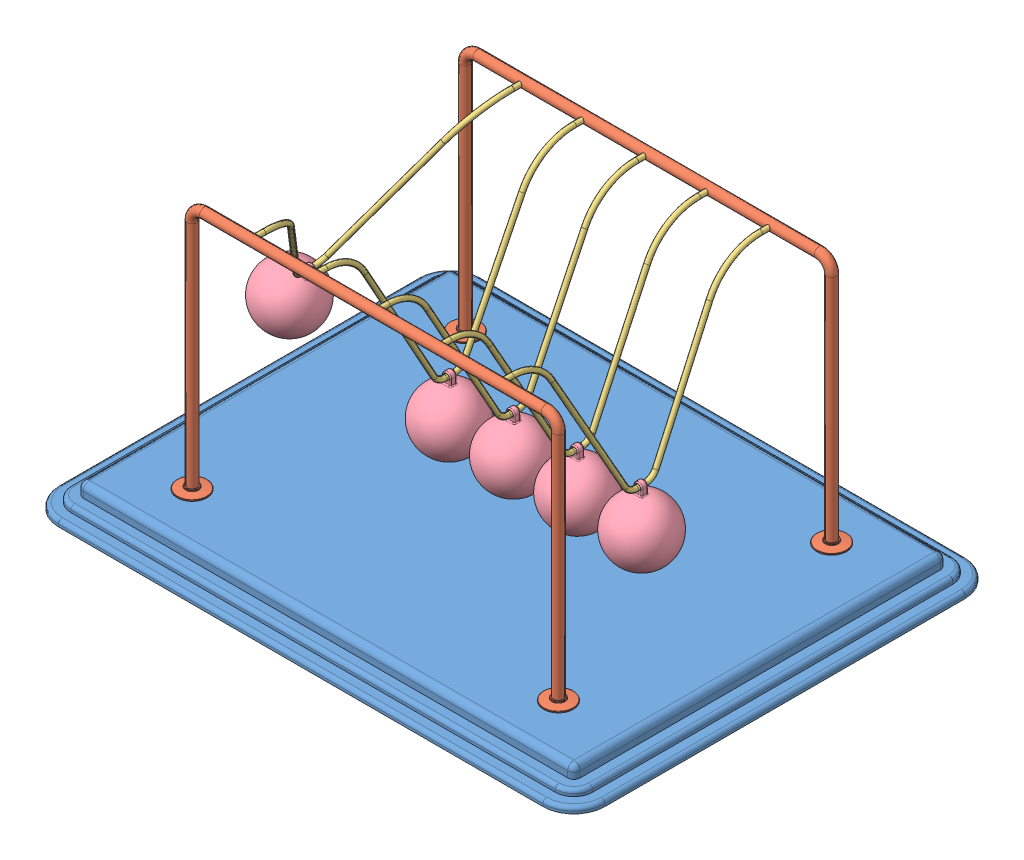
SolidWorks assembly Newtons Cradle NewtonsCradle 0232, configuration Default. Lengths in mm.
Overall size (440 222 340).
13 component instances, 4 part files, 34 mates.
Components (placement in the parent):
- Base NewtonsCradle 0232-1: Base NewtonsCradle 0232 [Default] at (-16.2968 -4.1587 11.425) size (440 20 340)
- frame NewtonsCradle 0232-1: frame NewtonsCradle 0232 [Default] at (-16.2968 144.4547 -98.575) size (319 202 24)
- frame NewtonsCradle 0232-2: frame NewtonsCradle 0232 [Default] at (-16.2968 144.4547 121.425) x (-1 0 0) z (0 0 -1) size (319 202 24)
- Hanging thing NewtonsCradle 0232-1: Hanging thing NewtonsCradle 0232 [Default] at (-157.6326 134.1825 11.425) x (0 0 1) z (-0.859985 0.510319 0) size (220 129 4)
- Hanging thing NewtonsCradle 0232-2: Hanging thing NewtonsCradle 0232 [Default] at (-66.576 122.8418 11.425) x (0 0 1) z (-0.999994 0.003446 0) size (220 129 4)
- Hanging thing NewtonsCradle 0232-3: Hanging thing NewtonsCradle 0232 [Default] at (-15.6923 122.8436 11.425) x (0 0 1) z (-0.999972 -0.007464 0) size (220 129 4)
- Hanging thing NewtonsCradle 0232-4: Hanging thing NewtonsCradle 0232 [Default] at (35.2213 122.8555 11.425) x (0 0 1) z (-0.999824 -0.018742 0) size (220 129 4)
- Hanging thing NewtonsCradle 0232-5: Hanging thing NewtonsCradle 0232 [Default] at (86.0287 122.8747 11.425) x (0 0 1) z (-0.999588 -0.028711 0) size (220 129 4)
- Sphere NewtonsCradle 0232-1: Sphere NewtonsCradle 0232 [Default] at (-195.3962 70.5436 11.425) x (0.859985 -0.510319 0) z (0 0 1) size (50 58.5 50)
- Sphere NewtonsCradle 0232-2: Sphere NewtonsCradle 0232 [Default] at (88.1533 48.9052 11.425) x (0.999588 0.028711 0) z (0 0 1) size (50 58.5 50)
- Sphere NewtonsCradle 0232-3: Sphere NewtonsCradle 0232 [Default] at (-15.14 48.8456 11.425) x (0.999972 0.007464 0) z (0 0 1) size (50 58.5 50)
- Sphere NewtonsCradle 0232-4: Sphere NewtonsCradle 0232 [Default] at (36.6081 48.8685 11.425) x (0.999824 0.018742 0) z (0 0 1) size (50 58.5 50)
- Sphere NewtonsCradle 0232-5: Sphere NewtonsCradle 0232 [Default] at (-66.831 48.8422 11.425) x (0.999994 -0.003446 0) z (0 0 1) size (50 58.5 50)
Mates (geometry in assembly coordinates):
- Coincident1: coincident anti-aligned: plane of Base-1 through (-211.2968 5.8413 156.425) normal (0 1 0); plane of frame-2 through (-175.7968 5.8413 121.425) normal (0 -1 0)
- Coincident2: coincident anti-aligned: plane of Base-1 through (-211.2968 5.8413 156.425) normal (0 1 0); plane of frame-1 through (143.2032 5.8413 -98.575) normal (0 -1 0)
- Concentric1: concentric anti-aligned: cylinder of frame-1 through (-116.2968 203.8413 -94.575) axis (0 0 -1) radius 2; cylinder of frame-2 through (-116.2968 203.8413 117.425) axis (0 0 1) radius 2
- Concentric2: concentric anti-aligned: cylinder of frame-1 through (83.7032 203.8413 -94.575) axis (0 0 -1) radius 2; cylinder of frame-2 through (83.7032 203.8413 117.425) axis (0 0 1) radius 2
- Distance1: distance = 60 mm: plane of frame-1 through (-16.2968 144.4547 -98.575) normal (0 0 1); line of Base-1 through (-211.2968 -12.1587 -158.575) axis (1 0 0)
- Distance2: distance = 60 mm: line of Base-1 through (178.7032 -12.1587 181.425) axis (-1 0 0); plane of frame-2 through (-16.2968 144.4547 121.425) normal (0 0 -1)
- Distance3: distance = 220 mm: plane of frame-2 through (-16.2968 144.4547 121.425) normal (-1 0 0); line of Base-1 through (-236.2968 -12.1587 156.425) axis (0 0 -1)
- Concentric3: concentric anti-aligned: cylinder of frame-1 through (-116.2968 203.8413 -94.575) axis (0 0 -1) radius 2; cylinder of Hanging thing-1 through (-116.2968 203.8413 111.425) axis (0 0 1) radius 2
- Concentric4: concentric anti-aligned: cylinder of frame-1 through (-116.2968 203.8413 -94.575) axis (0 0 -1) radius 2; cylinder of Hanging thing-1 through (-116.2968 203.8413 -98.575) axis (0 0 1) radius 2
- Concentric5: concentric aligned: cylinder of frame-2 through (-66.2968 203.8413 117.425) axis (0 0 1) radius 2; cylinder of Hanging thing-2 through (-66.2968 203.8413 111.425) axis (0 0 1) radius 2
- Concentric6: concentric aligned: cylinder of frame-2 through (-16.2968 203.8413 117.425) axis (0 0 1) radius 2; cylinder of Hanging thing-3 through (-16.2968 203.8413 111.425) axis (0 0 1) radius 2
- Concentric7: concentric aligned: cylinder of frame-2 through (33.7032 203.8413 117.425) axis (0 0 1) radius 2; cylinder of Hanging thing-4 through (33.7032 203.8413 111.425) axis (0 0 1) radius 2
- Concentric8: concentric aligned: cylinder of frame-2 through (83.7032 203.8413 117.425) axis (0 0 1) radius 2; cylinder of Hanging thing-5 through (83.7032 203.8413 111.425) axis (0 0 1) radius 2
- Coincident5: coincident anti-aligned: plane of frame-2 through (83.7032 203.8413 121.425) normal (0 0 -1); plane of Hanging thing-5 through (83.7032 203.8413 121.425) normal (0 0 1)
- Coincident6: coincident anti-aligned: plane of frame-2 through (33.7032 203.8413 121.425) normal (0 0 -1); plane of Hanging thing-4 through (33.7032 203.8413 121.425) normal (0 0 1)
- Coincident7: coincident anti-aligned: plane of frame-2 through (-16.2968 203.8413 121.425) normal (0 0 -1); plane of Hanging thing-3 through (-16.2968 203.8413 121.425) normal (0 0 1)
- Coincident8: coincident anti-aligned: plane of frame-2 through (-66.2968 203.8413 121.425) normal (0 0 -1); plane of Hanging thing-2 through (-66.2968 203.8413 121.425) normal (0 0 1)
- Coincident9: coincident anti-aligned: plane of frame-2 through (-116.2968 203.8413 121.425) normal (0 0 -1); plane of Hanging thing-1 through (-116.2968 203.8413 121.425) normal (0 0 1)
- Concentric9: concentric anti-aligned: cylinder of Hanging thing-1 through (-117.0163 78.8434 7.925) axis (0 0 1) radius 2; cylinder of Sphere-1 through (-117.0163 78.8434 13.925) axis (0 0 -1) radius 2
- Concentric13: concentric anti-aligned: cylinder of Hanging thing-2 through (-66.7276 78.842 7.925) axis (0 0 1) radius 2; cylinder of Sphere-5 through (-66.7276 78.842 13.925) axis (0 0 -1) radius 2
- Concentric15: concentric anti-aligned: cylinder of Hanging thing-3 through (-15.3639 78.8448 7.925) axis (0 0 1) radius 2; cylinder of Sphere-3 through (-15.3639 78.8448 13.925) axis (0 0 -1) radius 2
- Concentric16: concentric anti-aligned: cylinder of Hanging thing-5 through (87.292 78.8928 7.925) axis (0 0 1) radius 2; cylinder of Sphere-2 through (87.292 78.8928 13.925) axis (0 0 -1) radius 2
- Concentric17: concentric anti-aligned: cylinder of Hanging thing-4 through (36.0459 78.8632 7.925) axis (0 0 1) radius 2; cylinder of Sphere-4 through (36.0459 78.8632 13.925) axis (0 0 -1) radius 2
- Parallel1: parallel anti-aligned: plane of Hanging thing-1; plane of Sphere-1
- Coincident22: coincident anti-aligned: plane of Hanging thing-1; plane of Sphere-1
- Coincident12: coincident aligned: plane of Hanging thing-2 through (-66.576 122.8418 11.425) normal (0 0 1); plane of Sphere-5 through (-66.831 48.8422 11.425) normal (0 0 1)
- Coincident10: coincident aligned: plane of Hanging thing-1 through (-116.763 122.8426 11.425) normal (0 0 1); plane of Sphere-1 through (-118.5806 48.8842 11.425) normal (0 0 1)
- Coincident13: coincident anti-aligned: plane of Hanging thing-2 through (-66.576 122.8418 11.425) normal (-0.999994 0.003446 0); plane of Sphere-5 through (-66.831 48.8422 11.425) normal (0.999994 -0.003446 0)
- Coincident14: coincident anti-aligned: plane of Hanging thing-3 through (-15.6923 122.8436 11.425) normal (-0.999972 -0.007464 0); plane of Sphere-3 through (-15.14 48.8456 11.425) normal (0.999972 0.007464 0)
- Coincident15: coincident aligned: plane of Hanging thing-3 through (-15.6923 122.8436 11.425) normal (0 0 1); plane of Sphere-3 through (-15.14 48.8456 11.425) normal (0 0 1)
- Coincident18: coincident aligned: plane of Hanging thing-4 through (35.2213 122.8555 11.425) normal (0 0 1); plane of Sphere-4 through (36.6081 48.8685 11.425) normal (0 0 1)
- Coincident19: coincident anti-aligned: plane of Hanging thing-4 through (35.2213 122.8555 11.425) normal (-0.999824 -0.018742 0); plane of Sphere-4 through (36.6081 48.8685 11.425) normal (0.999824 0.018742 0)
- Coincident20: coincident anti-aligned: plane of Hanging thing-5 through (86.0287 122.8747 11.425) normal (-0.999588 -0.028711 0); plane of Sphere-2 through (88.1533 48.9052 11.425) normal (0.999588 0.028711 0)
- Coincident21: coincident aligned: plane of Hanging thing-5 through (86.0287 122.8747 11.425) normal (0 0 1); plane of Sphere-2 through (88.1533 48.9052 11.425) normal (0 0 1)
